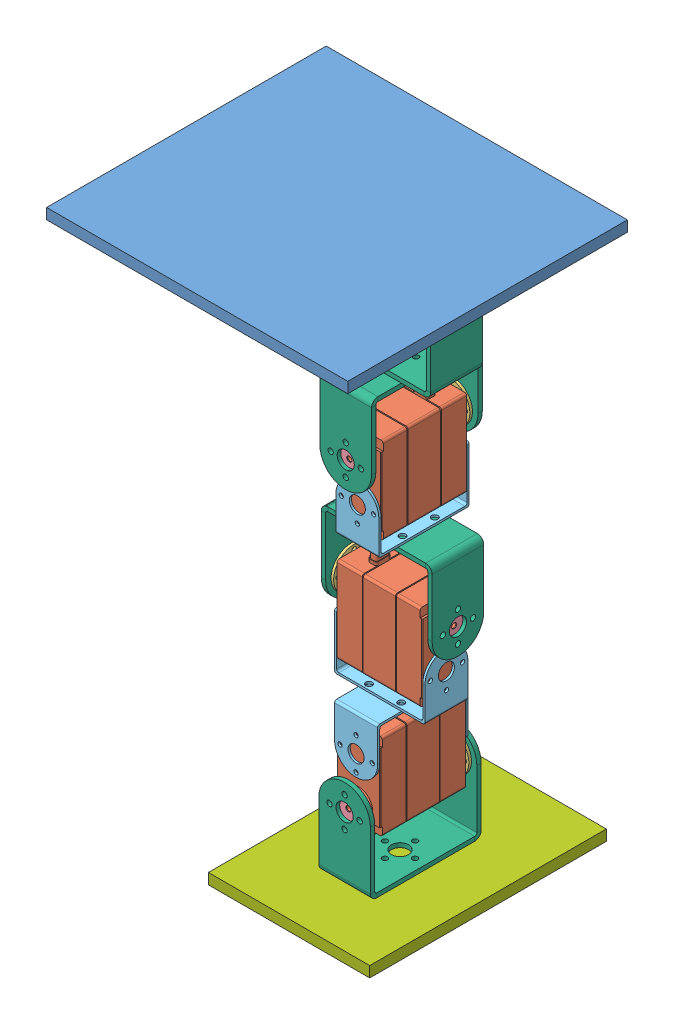
SolidWorks assembly Assem_Final, configuration Default. Lengths in mm.
Overall size (140 279.68 154.54).
26 component instances, 7 part files, 16 mates.
Components (placement in the parent):
- hip-plate-1: hip-plate [Default] at (56.1841 81.9924 80.1514) size (140 5 130)
- Assembly-1: Assembly [Default] at (24.006 72.7387 32.0964) x (0 -1 0) z (0 0 1) size (67.3 51.5 26.87)
  - dual shaft servo-1: dual shaft servo [Predeterminado] at (14.992 2.8195 38.2318) size (46.51 48.8 20.07)
  - accessory 1-1: accessory 1 [Predeterminado] at (35.7217 1.0691 58.2951) x (0.70399 0 0.71021) z (0.71021 0 -0.70399) size (19 2.2 19)
  - accessory 2-2: accessory 2 [Predeterminado] at (7.8921 46.4181 29.4135) x (-0.683613 0 -0.729844) z (0.729844 0 -0.683613) size (19 3.2 19)
  - support 1 ( dimensions check)-1: support 1 ( dimensions check) [Predeterminado] at (-9.1537 29.6478 38.798) x (0 1 0) z (0 0 -1) size (42 26 20)
  - U Bracket-1: U Bracket [Défaut] at (58.1419 23.5615 38.2647) x (0 -1 0) z (0 0 -1) size (51.5 42 24)
- Assembly-2: Assembly [Default] at (9.3028 -43.6451 46.7996) x (0 1 0) z (1 0 0) size (67.3 51.5 26.87)
  - dual shaft servo-1: dual shaft servo [Predeterminado] at (14.992 2.8195 38.2318) size (46.51 48.8 20.07)
  - accessory 1-1: accessory 1 [Predeterminado] at (35.7217 1.0691 58.2951) x (0.70399 0 0.71021) z (0.71021 0 -0.70399) size (19 2.2 19)
  - accessory 2-2: accessory 2 [Predeterminado] at (7.8921 46.4181 29.4135) x (-0.683613 0 -0.729844) z (0.729844 0 -0.683613) size (19 3.2 19)
  - support 1 ( dimensions check)-1: support 1 ( dimensions check) [Predeterminado] at (-9.1537 29.6478 38.798) x (0 1 0) z (0 0 -1) size (42 26 20)
  - U Bracket-1: U Bracket [Défaut] at (58.1419 23.5615 38.2647) x (0 -1 0) z (0 0 -1) size (51.5 42 24)
- Assembly-3: Assembly [Default] at (24.0393 -111.0408 107.9997) x (0 1 0) z (0 0 -1) size (67.3 51.5 26.87)
  - dual shaft servo-1: dual shaft servo [Predeterminado] at (14.992 2.8195 38.2318) size (46.51 48.8 20.07)
  - accessory 1-1: accessory 1 [Predeterminado] at (35.7217 1.0691 58.2951) x (0.70399 0 0.71021) z (0.71021 0 -0.70399) size (19 2.2 19)
  - accessory 2-2: accessory 2 [Predeterminado] at (7.8921 46.4181 29.4135) x (-0.683613 0 -0.729844) z (0.729844 0 -0.683613) size (19 3.2 19)
  - support 1 ( dimensions check)-1: support 1 ( dimensions check) [Predeterminado] at (-9.1537 29.6478 38.798) x (0 1 0) z (0 0 -1) size (42 26 20)
  - U Bracket-1: U Bracket [Défaut] at (58.1419 23.5615 38.2647) x (0 -1 0) z (0 0 -1) size (51.5 42 24)
- Assembly-4: Assembly [Default] at (85.2726 -129.4482 46.7664) x (0 -1 0) z (-1 0 0) size (67.3 51.5 26.87)
  - dual shaft servo-1: dual shaft servo [Predeterminado] at (14.992 2.8195 38.2318) size (46.51 48.8 20.07)
  - accessory 1-1: accessory 1 [Predeterminado] at (35.7217 1.0691 58.2951) x (0.70399 0 0.71021) z (0.71021 0 -0.70399) size (19 2.2 19)
  - accessory 2-2: accessory 2 [Predeterminado] at (7.8921 46.4181 29.4135) x (-0.683613 0 -0.729844) z (0.729844 0 -0.683613) size (19 3.2 19)
  - support 1 ( dimensions check)-1: support 1 ( dimensions check) [Predeterminado] at (-9.1537 29.6478 38.798) x (0 1 0) z (0 0 -1) size (42 26 20)
  - U Bracket-1: U Bracket [Défaut] at (58.1419 23.5615 38.2647) x (0 -1 0) z (0 0 -1) size (51.5 42 24)
- base-plate-1: base-plate [Default] at (64.602 -192.6901 51.2773) size (75 5 110)
Mates (geometry in assembly coordinates):
- Parallel1: parallel anti-aligned: plane of hip-plate-1 through (56.1841 81.9924 80.1514) normal (0 -1 0); plane of Assembly-1/support 1 ( dimensions check)-1 through (53.6538 81.8924 70.8944) normal (0 1 0)
- Distance2: distance = 0.1 mm anti-aligned: plane of hip-plate-1 through (56.1841 81.9924 80.1514) normal (0 -1 0); plane of Assembly-1/support 1 ( dimensions check)-1 through (53.6538 81.8924 70.8944) normal (0 1 0)
- Parallel4: parallel anti-aligned: plane of Assembly-1/U Bracket-1 through (73.3175 14.5968 58.3611) normal (0 -1 0); plane of Assembly-2/U Bracket-1 through (35.5675 14.4968 96.1111) normal (0 1 0)
- Concentric8: concentric anti-aligned: circle of Assembly-1/U Bracket-1; circle of Assembly-2/U Bracket-1
- Distance6: distance = 0.1 mm anti-aligned: plane of Assembly-1/U Bracket-1 through (73.3175 14.5968 58.3611) normal (0 -1 0); plane of Assembly-2/U Bracket-1 through (35.5675 14.4968 96.1111) normal (0 1 0)
- Parallel5: parallel anti-aligned: plane of Assembly-2/support 1 ( dimensions check)-1 through (48.1008 -52.7988 76.4474) normal (0 -1 0); plane of Assembly-3/U Bracket-1 through (73.3508 -52.8988 81.735) normal (0 1 0)
- Concentric9: concentric aligned: circle of Assembly-2/support 1 ( dimensions check)-1; circle of Assembly-3/U Bracket-1
- Distance8: distance = 0.1 mm anti-aligned: plane of Assembly-2/support 1 ( dimensions check)-1 through (48.1008 -52.7988 76.4474) normal (0 -1 0); plane of Assembly-3/U Bracket-1 through (73.3508 -52.8988 81.735) normal (0 1 0)
- Perpendicular13: perpendicular: plane of Assembly-1/U Bracket-1 through (71.3175 17.5968 82.3611) normal (0 0 1); line of Assembly-2/U Bracket-1 through (47.5675 14.4968 96.1111) axis (0 0 -1)
- Perpendicular14: perpendicular: plane of Assembly-2/support 1 ( dimensions check)-1 through (37.6008 -51.7988 48.735) normal (-1 0 0); plane of Assembly-3/U Bracket-1 through (23.8508 -55.8988 81.735) normal (0 0 1)
- Parallel6: parallel anti-aligned: plane of Assembly-3/support 1 ( dimensions check)-1 through (53.6871 -120.1945 69.2017) normal (0 -1 0); plane of Assembly-4/support 1 ( dimensions check)-1 through (46.4746 -120.2945 76.4142) normal (0 1 0)
- Concentric10: concentric anti-aligned: circle of Assembly-3/support 1 ( dimensions check)-1; circle of Assembly-4/support 1 ( dimensions check)-1
- Perpendicular15: perpendicular: plane of Assembly-3/support 1 ( dimensions check)-1 through (25.9746 -119.1945 79.7017) normal (0 0 1); line of Assembly-4/support 1 ( dimensions check)-1 through (36.9746 -121.2945 88.7017) axis (0 0 -1)
- Distance10: distance = 0.1 mm anti-aligned: plane of Assembly-3/support 1 ( dimensions check)-1 through (53.6871 -120.1945 69.2017) normal (0 -1 0); plane of Assembly-4/support 1 ( dimensions check)-1 through (46.4746 -120.2945 76.4142) normal (0 1 0)
- Parallel10: parallel anti-aligned: plane of Assembly-4/U Bracket-1 through (59.0078 -187.5901 96.0779) normal (0 -1 0); plane of base-plate-1 through (64.602 -187.6901 51.2773) normal (0 1 0)
- Distance13: distance = 0.1 mm anti-aligned: plane of base-plate-1 through (64.602 -187.6901 51.2773) normal (0 1 0); plane of Assembly-4/U Bracket-1 through (59.0078 -187.5901 96.0779) normal (0 -1 0)
